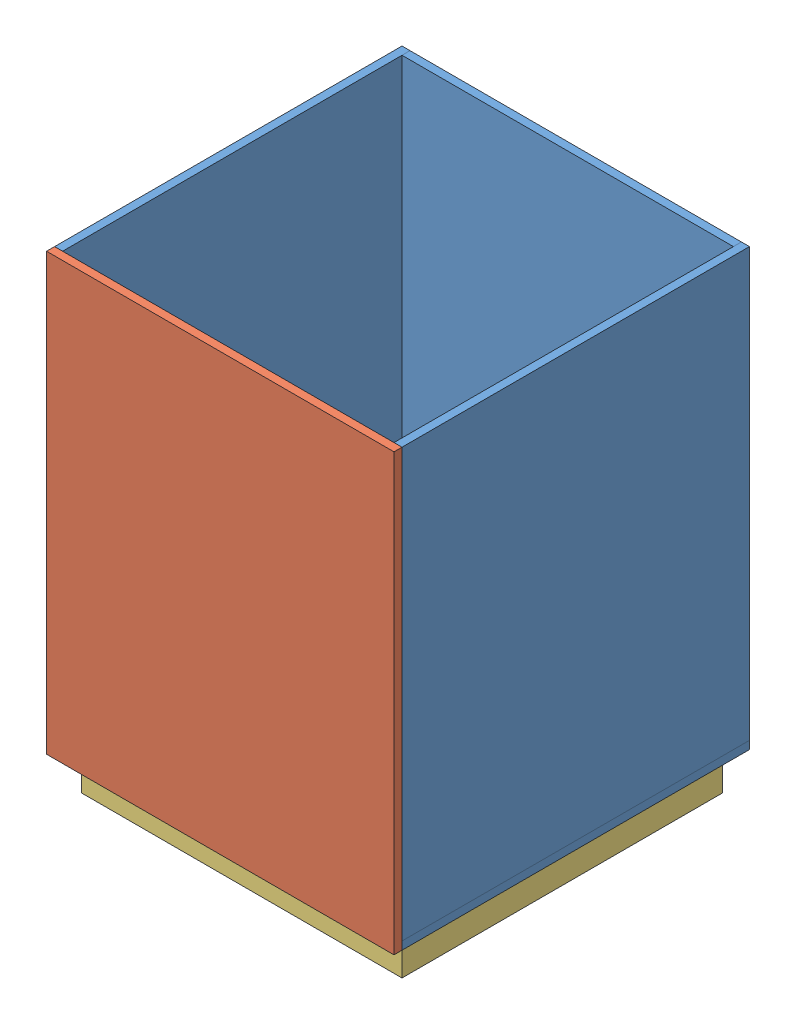
SolidWorks assembly ormar, configuration Default. Lengths in mm.
Overall size (650 885 665).
3 component instances, 3 part files, 12 mates.
Components (placement in the parent):
- Part2^ormar-1: Part2^ormar [Default] at (-80.7012 141.6915 27.7146) x (1 0 0) z (0 1 0) size (650 650 815) (virtual)
- Part3^ormar-1: Part3^ormar [Default] at (-80.7012 141.6915 352.7146) x (-1 0 0) z (0 0 1) size (650 815 15) (virtual)
- Part4^ormar-1: Part4^ormar [Default] at (-80.7012 141.6915 27.7146) x (-1 0 0) z (0 -1 0) size (600 600 70) (virtual)
Mates (geometry in assembly coordinates):
- InPlace1: in place: plane of ? through (-49.8455 44.4835 30.0506) normal (0 1 0); plane of ? through (0 44.4835 0) normal (0 1 0); moOrthogonalPlaneRef_w of ? through (-49.8455 44.4835 30.0506) normal (0 1 0); plane of ? through (0 44.4835 0) normal (0 0 -1); plane of ? through (-49.8455 44.4835 30.0506) normal (0 1 0); plane of ? through (0 44.4835 0) normal (1 0 0); plane of ? through (-49.8455 44.4835 30.0506) normal (0 1 0); unknown of Part2^ormar-1
- Coincident1: coincident aligned: plane of ?; plane of Part2^ormar-1
- Coincident2: coincident aligned: moOrthogonalPlaneRef_w of Part1-1 through (-49.8455 44.4835 30.0506) normal (0 0 -1); plane of Part2^ormar-1 through (-80.7012 141.6915 27.7146) normal (0 0 -1)
- Coincident3: coincident anti-aligned: moOrthogonalPlaneRef_w of Part1-1 through (-49.8455 44.4835 30.0506) normal (-1 0 0); plane of Part2^ormar-1 through (-80.7012 141.6915 27.7146) normal (1 0 0)
- InPlace2: in place: plane of ? through (-374.8455 859.4835 355.0506) normal (0 0 1); plane of ? through (0 0 355.0506) normal (0 0 1); plane of ? through (-374.8455 859.4835 355.0506) normal (0 0 1); plane of ? through (0 0 355.0506) normal (0 1 0); plane of ? through (-374.8455 859.4835 355.0506) normal (0 0 1); plane of ? through (0 0 355.0506) normal (1 0 0); plane of Part2^ormar-1 through (-405.7012 956.6915 352.7146) normal (0 0 1); unknown of Part3^ormar-1
- Coincident4: coincident aligned: plane of Part2^ormar-1; plane of Part3^ormar-1
- Coincident5: coincident aligned: moOrthogonalPlaneRef_w of Part2^ormar-1 through (-80.7012 141.6915 352.7146) normal (0 -1 0); plane of Part3^ormar-1 through (-80.7012 141.6915 352.7146) normal (0 -1 0)
- Coincident6: coincident anti-aligned: moOrthogonalPlaneRef_w of Part2^ormar-1 through (-80.7012 141.6915 352.7146) normal (1 0 0); plane of Part3^ormar-1 through (-80.7012 141.6915 352.7146) normal (-1 0 0)
- InPlace3: in place: plane of ? through (-49.8455 44.4835 30.0506) normal (0 -1 0); plane of ? through (0 44.4835 0) normal (0 -1 0); plane of ? through (-49.8455 44.4835 30.0506) normal (0 -1 0); plane of ? through (0 44.4835 0) normal (0 0 -1); plane of ? through (-49.8455 44.4835 30.0506) normal (0 -1 0); plane of ? through (0 44.4835 0) normal (-1 0 0); plane of Part2^ormar-1 through (-80.7012 141.6915 27.7146) normal (0 -1 0); unknown of Part4^ormar-1
- Coincident1: coincident aligned: plane of Part2^ormar-1; plane of Part4^ormar-1
- Coincident2: coincident aligned: moOrthogonalPlaneRef_w of Part2^ormar-1 through (-80.7012 141.6915 27.7146) normal (0 0 -1); plane of Part4^ormar-1 through (-80.7012 141.6915 27.7146) normal (0 0 -1)
- Coincident3: coincident anti-aligned: moOrthogonalPlaneRef_w of Part2^ormar-1 through (-80.7012 141.6915 27.7146) normal (1 0 0); plane of Part4^ormar-1 through (-80.7012 141.6915 27.7146) normal (-1 0 0)
